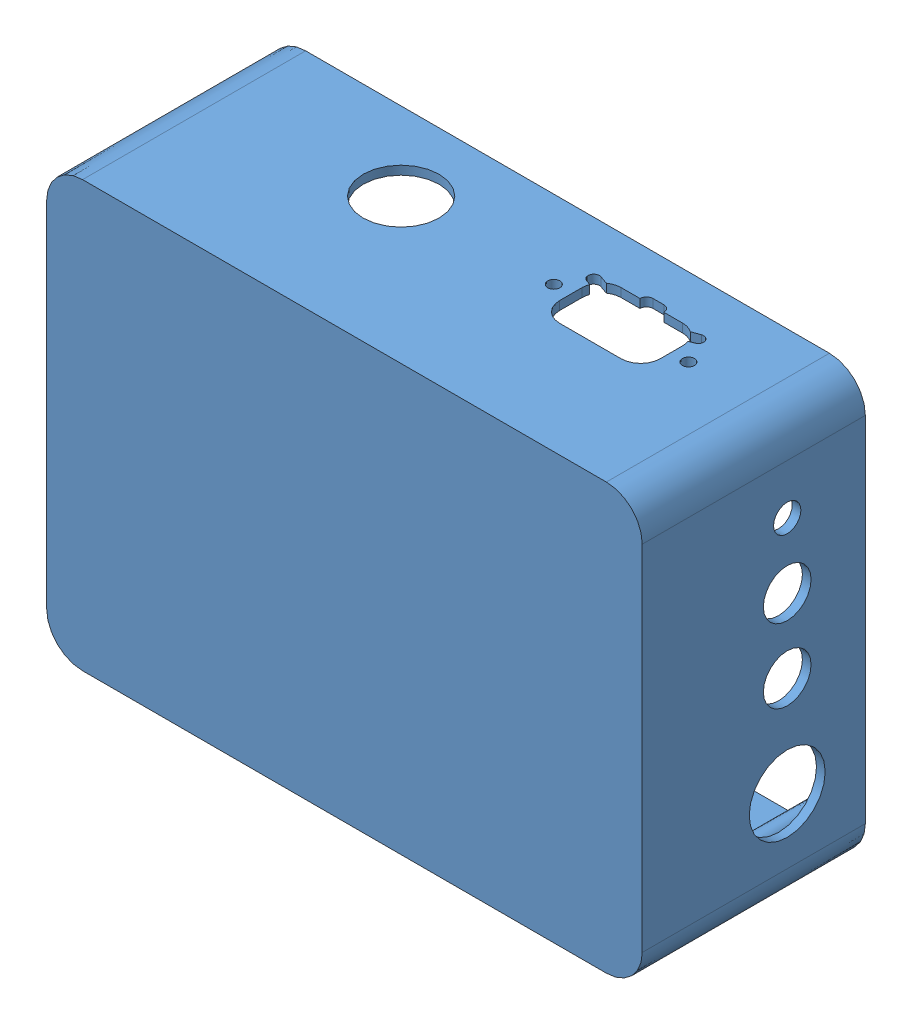
SolidWorks assembly Charging, configuration Default. Lengths in mm.
Overall size (174.27 124.46 70.23).
2 component instances, 2 part files, 3 mates.
Components (placement in the parent):
- Charging Box-1: Charging Box [Default] at (-140.0939 -70.0425 61.308) x (1 0 0) z (0 1 0) size (174.27 70.23 124.46)
- Charging Board-1: Charging Board [Default] at (-15.3074 -39.233 60.3174) x (0.999998 0.001923 0) z (0 0 -1) size (82.71 83.98 0.99)
Mates (geometry in assembly coordinates):
- Coincident2: coincident: plane of Charging Box-1 through (-216.7286 -18.3125 61.308) normal (0 0 -1); plane of Charging Board-1 through (-186.5886 -127.1925 61.308) normal (0 0 1)
- Distance2: distance = 2.54 mm: plane of Charging Board-1 through (-104.0385 -127.1925 60.3174) normal (0 -1 0); plane of Charging Box-1 through (-140.0939 -129.7325 0.348) normal (0 1 0)
- Distance3: distance = 38.1 mm: point of Charging Board-1; plane of Charging Box-1 through (-224.6886 -70.0425 0.348) normal (1 0 0)
